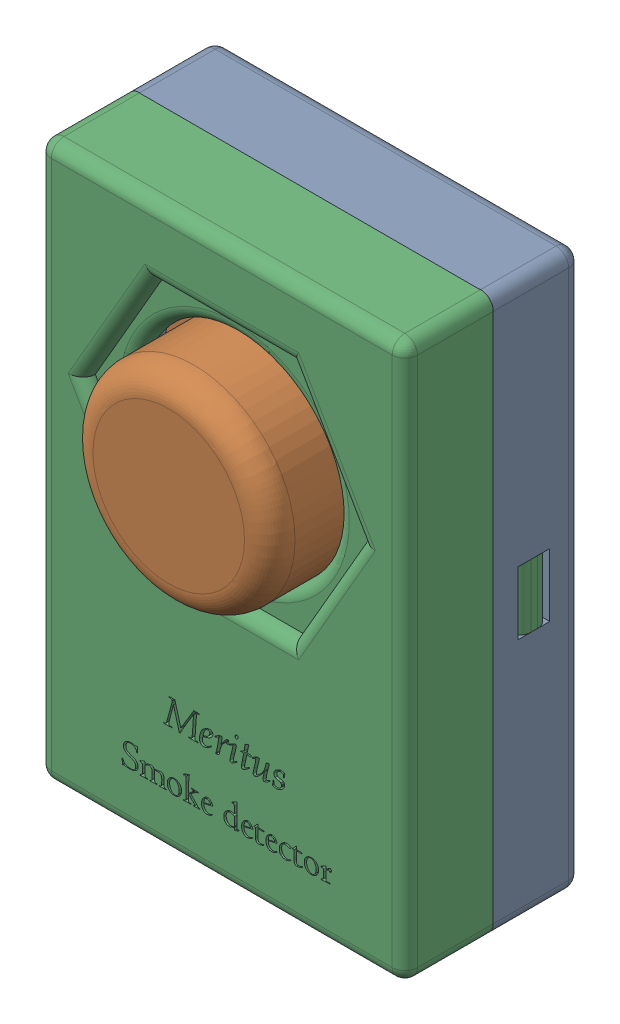
SolidWorks assembly SMOKE, configuration Default. Lengths in mm.
Overall size (29 44 18.3).
3 component instances, 3 part files, 0 mates.
Components (placement in the parent):
- smoke_base-1: smoke_base [Default] at (1.1662 2.2812 3.6386) size (29 44 7)
- Smoke-1: Smoke [Default] at (1.2912 8.2062 5.6386) size (19.75 31.95 16.3)
- smoke_top-1: smoke_top [Default] at (1.1662 5.3062 17.6121) x (-1 0 0) z (0 0 -1) size (29 44 11.5)
